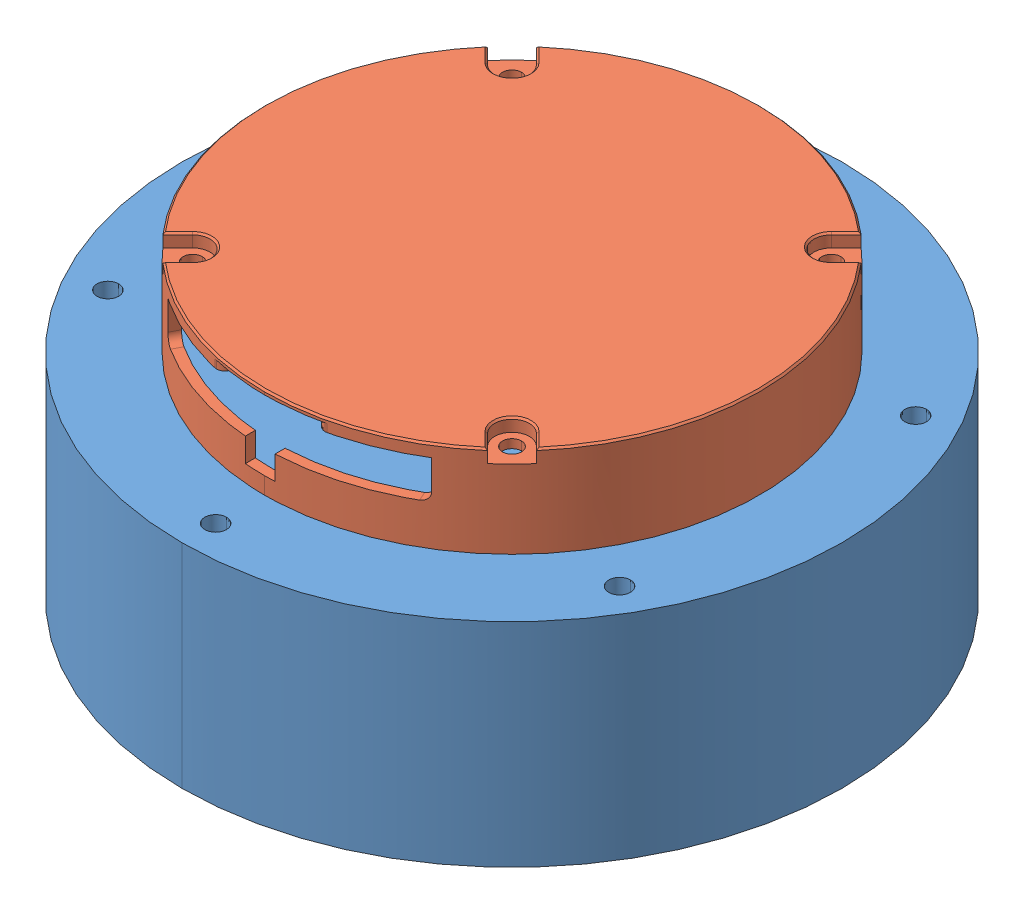
SolidWorks assembly DM 6210 3d 20230507, configuration 默认. Lengths in mm.
Overall size (76 36.5 76).
3 component instances, 2 part files, 0 mates.
Components (placement in the parent):
- DM 6210 3d 20230507.STEP-1: DM 6210 3d 20230507.STEP [默认] at origin size (76 36.5 76)
  - DM 6210 3D.STEP-1: DM 6210 3D.STEP [默认] at origin size (76 26 76)
  - 6210 ________________.STEP-1: 6210 ________________.STEP [默认] at (0 35 0) x (1 0 0) z (0 0 -1) size (57 10.5 57)
